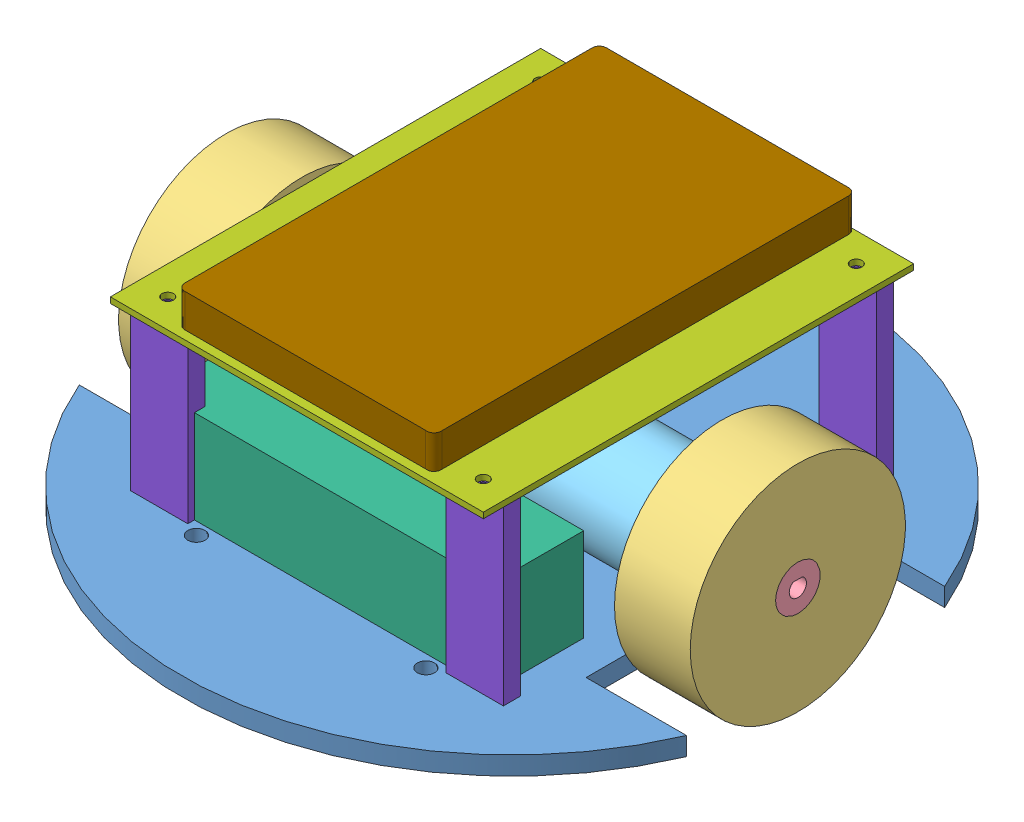
SolidWorks assembly full_robot, configuration Default. Lengths in mm.
Overall size (211.66 92.15 230).
18 component instances, 9 part files, 25 mates.
Components (placement in the parent):
- base-1: base [Default] at (26.2999 120.3064 207.7798) size (211.66 6.4 230)
- full_pillow-1: full_pillow [Default] at (9.2986 116.4099 227.4734) x (0 0 1) z (-1 0 0) size (75 75 92.2)
  - mancal-1: mancal [Default] at (-12.6936 10.2964 49.8287) size (38 38 4.8)
  - roda-1: roda [Default] at (-19.6936 29.2964 56.2287) size (75 75 26.4)
  - bucha-1: bucha [Default] at (-19.6936 29.2964 82.6287) x (-1 0 0) z (0 -1 0) size (15.6 26 15.6)
  - motor-1: motor [Default] at (-19.6936 29.2964 -9.5713) size (37 37 71)
- full_pillow-4: full_pillow [Default] at (43.3013 116.4099 188.0862) x (0 0 -1) z (1 0 0) size (75 75 92.2)
  - mancal-1: mancal [Default] at (-12.6936 10.2964 49.8287) size (38 38 4.8)
  - roda-1: roda [Default] at (-19.6936 29.2964 56.2287) size (75 75 26.4)
  - bucha-1: bucha [Default] at (-19.6936 29.2964 82.6287) x (-1 0 0) z (0 -1 0) size (15.6 26 15.6)
  - motor-1: motor [Default] at (-19.6936 29.2964 -9.5713) size (37 37 71)
- bateria-1: bateria [Default] at (-32.2001 142.9064 257.3798) x (0 0 -1) z (1 0 0) size (32.2 32.4 117)
- base2-1: base2 [Default] at (26.2999 186.7064 207.7798) size (130 2 150)
- coluna-1: coluna [Default] at (-28.7001 156.7064 139.7798) size (20 60 6)
- coluna-2: coluna [Default] at (81.2999 156.7064 269.7798) size (20 60 6)
- coluna-3: coluna [Default] at (81.2999 156.7064 139.7798) size (20 60 6)
- coluna-4: coluna [Default] at (-28.7001 156.7064 269.7798) size (20 60 6)
- PowerBank-1: PowerBank [Default] at (26.4371 186.7064 206.2798) x (0 0 1) z (-1 0 0) size (147.05 13.65 89.42)
Mates (geometry in assembly coordinates):
- Coincident1: coincident anti-aligned: plane of base-1 through (26.2999 126.7064 207.7798) normal (0 1 0); plane of full_pillow-1/mancal-1 through (-40.5301 126.7064 214.7798) normal (0 -1 0)
- Concentric1: concentric anti-aligned: circle of base-1; cylinder of full_pillow-1/mancal-1 through (-40.5301 136.7064 207.0298) axis (0 -1 0) radius 2
- Concentric2: concentric anti-aligned: cylinder of base-1 through (-40.5301 120.3064 222.5298) axis (0 1 0) radius 1.75; cylinder of full_pillow-1/mancal-1 through (-40.5301 136.7064 222.5298) axis (0 -1 0) radius 2
- Coincident4: coincident anti-aligned: plane of base-1 through (26.2999 126.7064 207.7798) normal (0 1 0); plane of full_pillow-4/mancal-1 through (93.13 126.7064 200.7798) normal (0 -1 0)
- Concentric5: concentric anti-aligned: cylinder of base-1 through (93.13 120.3064 208.5298) axis (0 1 0) radius 1.75; cylinder of full_pillow-4/mancal-1 through (93.13 136.7064 208.5298) axis (0 -1 0) radius 2
- Concentric6: concentric anti-aligned: cylinder of base-1 through (93.13 120.3064 193.0298) axis (0 1 0) radius 1.75; cylinder of full_pillow-4/mancal-1 through (93.13 136.7064 193.0298) axis (0 -1 0) radius 2
- Coincident5: coincident anti-aligned: plane of base-1 through (26.2999 126.7064 207.7798) normal (0 1 0); plane of bateria-1 through (84.7999 126.7064 273.4798) normal (0 -1 0)
- Parallel1: parallel aligned: plane of base-1 through (97.13 119.2064 162.7798) normal (1 0 0); plane of bateria-1 through (84.7999 142.9064 257.3798) normal (1 0 0)
- Width1: width anti-aligned: plane of bateria-1 through (84.7999 142.9064 257.3798) normal (1 0 0); plane of bateria-1 through (-32.2001 142.9064 257.3798) normal (-1 0 0); plane of base-1 through (-44.5301 119.2064 162.7798) normal (-1 0 0); plane of base-1 through (97.13 119.2064 162.7798) normal (1 0 0)
- Distance1: distance = 15 mm anti-aligned: plane of bateria-1 through (84.7999 126.7064 241.2798) normal (0 0 -1); cylinder of full_pillow-1/motor-1 through (-38.1301 145.7064 207.7798) axis (1 0 0) radius 18.5
- Coincident7: coincident anti-aligned: plane of base-1 through (26.2999 126.7064 207.7798) normal (0 1 0); plane of coluna-2 through (71.2999 126.7064 275.7798) normal (0 -1 0)
- Coincident8: coincident anti-aligned: plane of base-1 through (26.2999 126.7064 207.7798) normal (0 1 0); plane of coluna-4 through (-38.7001 126.7064 275.7798) normal (0 -1 0)
- Coincident9: coincident anti-aligned: plane of base-1 through (26.2999 126.7064 207.7798) normal (0 1 0); plane of coluna-3 through (71.2999 126.7064 145.7798) normal (0 -1 0)
- Coincident10: coincident anti-aligned: plane of base-1 through (26.2999 126.7064 207.7798) normal (0 1 0); plane of coluna-3 through (71.2999 126.7064 145.7798) normal (0 -1 0)
- Concentric7: concentric aligned: circle of base2-1; circle of coluna-1
- Concentric8: concentric aligned: circle of base2-1; circle of coluna-3
- Concentric9: concentric aligned: circle of base2-1; circle of coluna-2
- Concentric10: concentric aligned: circle of base2-1; circle of coluna-4
- Coincident11: coincident anti-aligned: plane of base2-1 through (26.2999 186.7064 207.7798) normal (0 -1 0); plane of coluna-4 through (-38.7001 186.7064 275.7798) normal (0 1 0)
- Coincident12: coincident anti-aligned: plane of base-1 through (26.2999 126.7064 207.7798) normal (0 1 0); plane of coluna-1 through (-38.7001 126.7064 145.7798) normal (0 -1 0)
- Width3: width anti-aligned: plane of base2-1 through (-38.7001 188.7064 282.7798) normal (-1 0 0); plane of base2-1 through (91.2999 188.7064 282.7798) normal (1 0 0); plane of base-1 through (97.13 119.2064 162.7798) normal (1 0 0); plane of base-1 through (-44.5301 119.2064 162.7798) normal (-1 0 0)
- Width4: width anti-aligned: plane of base2-1 through (-38.7001 188.7064 132.7798) normal (0 0 -1); plane of base2-1 through (-38.7001 188.7064 282.7798) normal (0 0 1); plane of base-1 through (-79.5301 119.2064 162.7798) normal (0 0 1); plane of base-1 through (-79.5301 119.2064 252.7798) normal (0 0 -1)
- Coincident22: coincident: plane of base2-1 through (26.2999 186.7064 207.7798) normal (0 -1 0); line of PowerBank-1 through (68.6371 186.7064 132.7798) axis (-1 0 0)
- Coincident26: coincident aligned: plane of base2-1 through (-38.7001 188.7064 132.7798) normal (0 0 -1); plane of PowerBank-1 through (-15.7629 200.3564 132.7798) normal (0 0 -1)
- Parallel3: parallel anti-aligned: plane of coluna-4 through (-18.7001 186.7064 275.7798) normal (1 0 0); plane of PowerBank-1 through (-18.2629 200.3564 277.2798) normal (-1 0 0)
